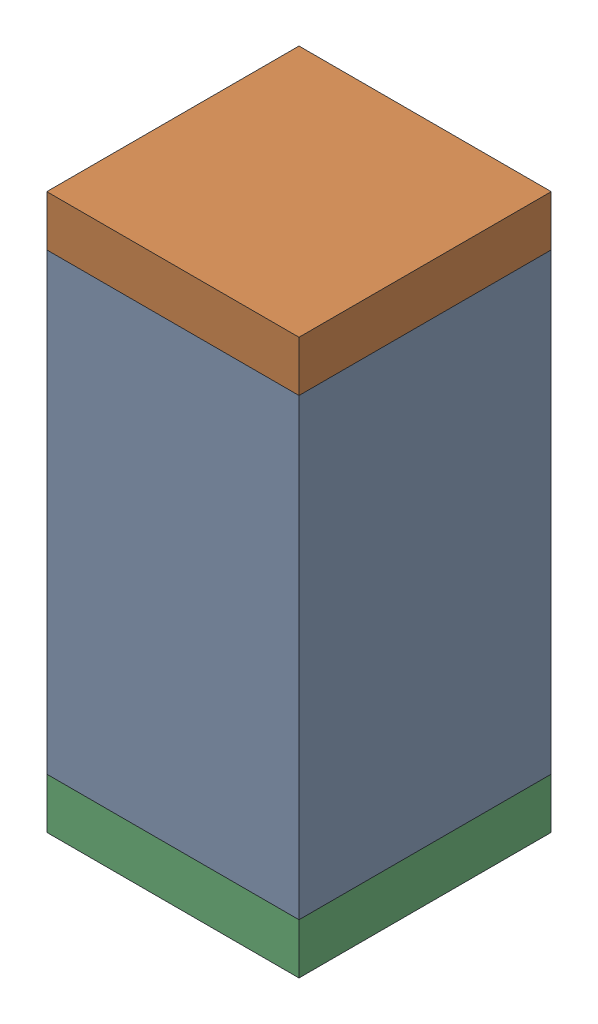
SolidWorks assembly C34, configuration Default. Lengths in mm.
Overall size (0.5 1.1 0.5).
6 component instances, 2 part files, 0 mates.
Components (placement in the parent):
- 791586336-1: 791586336 [Default] at (113.05 30.8 0) size (0.5 0.9 0.5)
  - Extruded_8-1: Extruded_8 [Default] at origin size (0.5 0.9 0.5)
- 810157360-1: 810157360 [Default] at (113.05 31.3 0) size (0.5 0.1 0.5)
  - Extruded_9-1: Extruded_9 [Default] at origin size (0.5 0.1 0.5)
- 810157360-2: 810157360 [Default] at (113.05 30.3 0) size (0.5 0.1 0.5)
  - Extruded_9-1: Extruded_9 [Default] at origin size (0.5 0.1 0.5)
